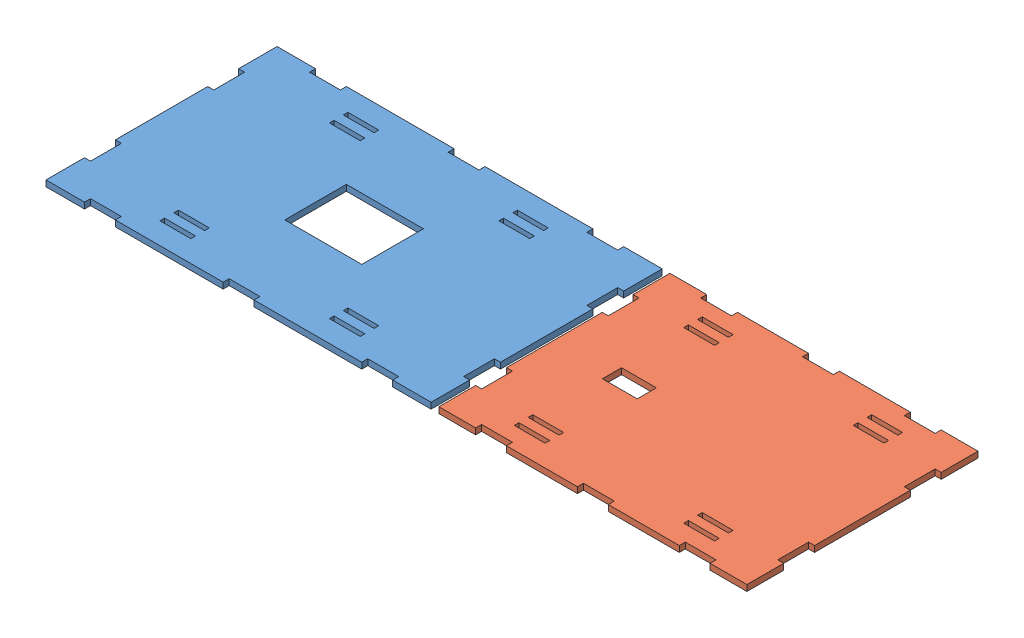
SolidWorks assembly Plastic Parts 2, configuration Default. Lengths in mm.
Overall size (455 3.9 150).
2 component instances, 2 part files, 3 mates.
Components (placement in the parent):
- Baseplate-1: Baseplate [Default] at (42.9564 111.6484 229.9297) size (250 3.9 150)
- Chassis Base-1: Chassis Base [Default] at (272.9564 111.6484 229.9297) size (200 3.9 150)
Mates (geometry in assembly coordinates):
- Coincident1: coincident aligned: plane of Baseplate-1 through (42.9564 115.5484 229.9297) normal (0 1 0); plane of Chassis Base-1 through (272.9564 115.5484 229.9297) normal (0 1 0)
- Distance1: distance = 5 mm anti-aligned: plane of Chassis Base-1 through (172.9564 115.5484 198.8297) normal (-1 0 0); plane of Baseplate-1 through (167.9564 115.5484 199.9297) normal (1 0 0)
- Coincident3: coincident aligned: plane of Baseplate-1 through (142.9564 115.5484 304.9297) normal (0 0 1); plane of Chassis Base-1 through (172.9564 115.5484 304.9297) normal (0 0 1)
